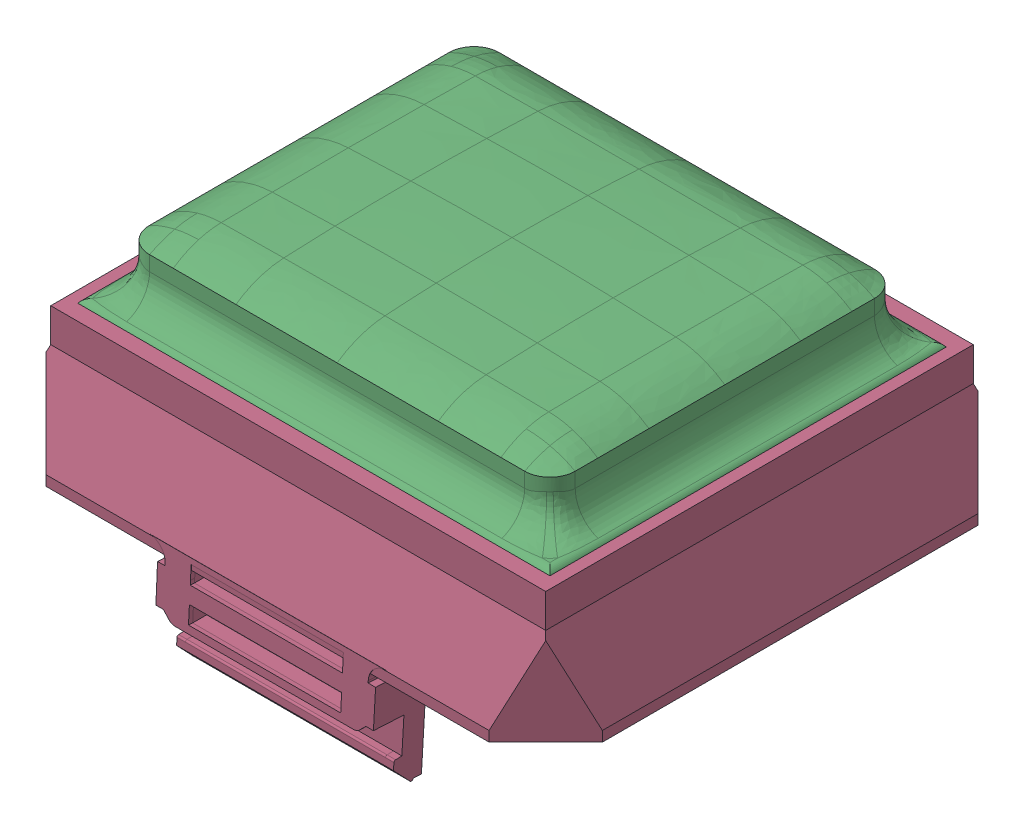
SolidWorks assembly Board, configuration 默认. Lengths in mm.
Overall size (33 18.27 29.5).
5 component instances, 5 part files, 13 mates.
Components (placement in the parent):
- NewContilensall-1: NewContilensall [默认] at origin size (28.33 2.18 23.83)
- NewInsideSkin_conti-1: NewInsideSkin_conti [默认] at (0.0001 0 0.2499) size (23.8 5.48 19.29)
- NewContiTopskin-1: NewContiTopskin [默认] at (0.0001 2 0.2499) size (28.02 6.25 23.52)
- NewContiSupportBase-2: NewContiSupportBase [默认] at origin size (33 14.02 29.5)
- Newcontinuous-1: Newcontinuous [默认] at (-10.2499 23.3 7.7499) x (1 0 0) z (0 1 0) size (22 16 0.4)
Mates (geometry in assembly coordinates):
- 同心2: concentric anti-aligned: cylinder of InsideSkin_conti-1 through (10.8751 17.7531 8.6249) axis (0 1 0) radius 0.7; cylinder of Board3Con1612611OriginalSkin_TOP-1 through (10.8751 24 8.6249) axis (0 -1 0) radius 0.7
- 同心3: concentric anti-aligned: cylinder of InsideSkin_conti-1 through (10.8751 17.7531 -9.1251) axis (0 1 0) radius 0.7; cylinder of Board3Con1612611OriginalSkin_TOP-1 through (10.8751 24 -9.1251) axis (0 -1 0) radius 0.7
- 重合4: coincident aligned: plane of InsideSkin_conti-1 through (10.8751 19 -9.1251) normal (0 -1 0); plane of Board3Con1612611OriginalSkin_TOP-1 through (0.0001 19 0.2499) normal (0 -1 0)
- 重合6: coordinate: point of NewContiSupportBase-2
- 重合7: coincident anti-aligned: plane of lensall-1 through (13.75 19 -11.5) normal (0.939693 0.34202 0); plane of NewContiSupportBase-2 through (13.75 19 12.7803) normal (-0.939693 -0.34202 0)
- 同心5: concentric aligned: cylinder of lensall-1 through (13.3294 18.6938 -11.0794) axis (-0.323616 0.889126 0.323616) radius 0.5; cylinder of NewContiSupportBase-2 through (10.7866 25.6801 -8.5366) axis (-0.323616 0.889126 0.323616) radius 0.5
- 重合8: coincident anti-aligned: plane of lensall-1 through (0 18 0) normal (0 -1 0); plane of NewContiSupportBase-2 through (0 18 0) normal (0 1 0)
- 重合9: coincident anti-aligned: plane of lensall-1 through (0 19 0) normal (0 1 0); plane of Board3Con1612611OriginalSkin_TOP-1 through (0.0001 19 0.2499) normal (0 -1 0)
- 重合10: coincident anti-aligned: plane of Board3Con1612611OriginalSkin_TOP-1 through (0.0001 19 11.7499) normal (0 0 1); plane of NewContiSupportBase-2 through (-13.5999 21 11.7499) normal (0 0 -1)
- 重合11: coincident anti-aligned: plane of Board3Con1612611OriginalSkin_TOP-1 through (14.0001 19 0.2499) normal (1 0 0); plane of NewContiSupportBase-2 through (14.0001 21 11.7499) normal (-1 0 0)
- 宽度1: width aligned: plane of InsideSkin_conti-1 through (-11.3749 17.7531 -9.8251) normal (0 0 -1); plane of InsideSkin_conti-1 through (-11.3749 17.7531 9.3249) normal (0 0 1); plane of continuous-1 through (-11.2499 23.3 -8.2501) normal (0 0 -1); plane of continuous-1 through (-10.2499 23.7 7.7499) normal (0 0 1)
- 宽度2: width aligned: plane of continuous-1 through (-11.2499 23.3 -3.2352) normal (-1 0 0); plane of continuous-1 through (10.7501 23.7 7.7499) normal (1 0 0); plane of InsideSkin_conti-1 through (-12.0749 17.7531 -9.1251) normal (-1 0 0); plane of InsideSkin_conti-1 through (11.5751 17.7531 -9.1251) normal (1 0 0)
- 重合12: coincident aligned: line of InsideSkin_conti-1 through (-10.2499 23.7 -5.2501) axis (0 0 -1); line of continuous-1 through (-10.2499 23.7 -5.2501) axis (0 0 -1)
